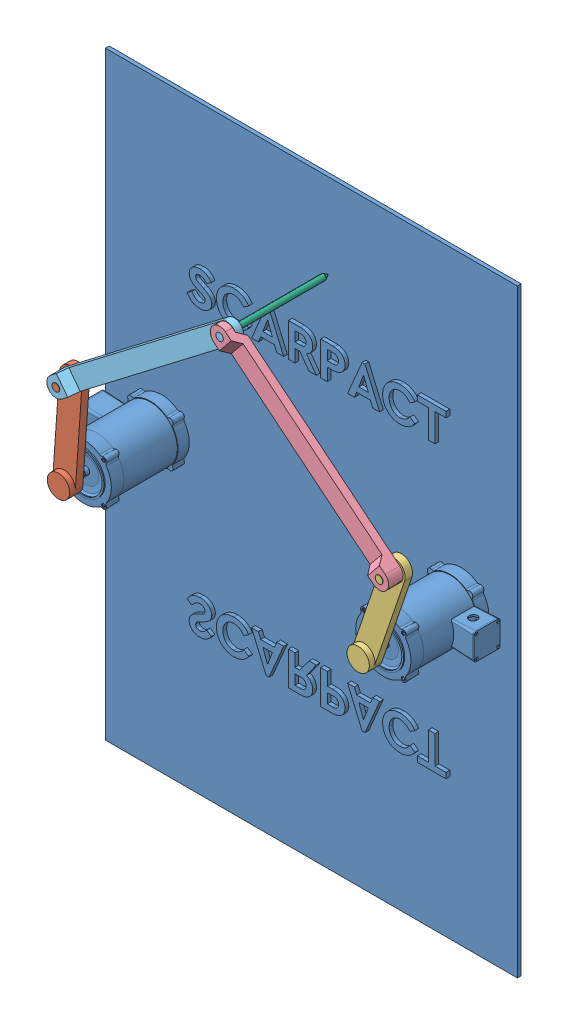
SolidWorks assembly SCARPACT, configuration Default. Lengths in mm.
Overall size (1100 1600 310.35).
6 component instances, 6 part files, 14 mates.
Components (placement in the parent):
- Base-1: Base [Default] at origin size (1100 1600 270.35)
- Link A1-1: Link A1 [Default] at (8.7744 124.6917 250.35) x (0.070195 0.997533 0) z (0 0 1) size (310 60 60)
- Link A2-1: Link A2 [Default] at (840.3034 118.3243 250.35) x (0.322428 0.946594 0) z (0 0 1) size (310 60 60)
- Link B1-1: Link B1 [Default] at (667.3575 410.2852 270.35) x (-0.775453 0.631406 0) z (0 0 1) size (600 50 39)
- Link B2-1: Link B2 [Default] at (250.4261 427.8389 269.85) x (0.793744 0.608252 0) z (0 0 1) size (600 50 39)
- Endeffector-1: Endeffector [Default] at (293.9198 383.4526 260.35) x (-0.62425 -0.781224 0) z (0 0 -1) size (15 15 250.35)
Mates (geometry in assembly coordinates):
- Coincident1: coincident aligned: plane of Base_Modified-1 through (0 0 0) normal (0 0 1)
- Coincident2: coincident aligned: plane of Base_Modified-1 through (0 0 0) normal (0 1 0)
- Concentric1: concentric anti-aligned: cylinder of Base_Modified-1 through (0 0 260.35) axis (0 0 1) radius 7.9375; cylinder of Link A1-1 through (0 0 260.35) axis (0 0 -1) radius 9.8426
- Coincident4: coincident anti-aligned: plane of Base_Modified-1 through (0 0 260.35) normal (0 0 1); plane of Link A1-1 through (0 0 260.35) normal (0 0 -1)
- Concentric3: concentric aligned: cylinder of Link A1-1 through (17.5487 249.3833 300.35) axis (0 0 -1) radius 10; cylinder of Link B2-1 through (17.5487 249.3833 299.35) axis (0 0 -1) radius 10
- Coincident6: coincident anti-aligned: plane of Link A1-1 through (0 0 260.35) normal (0 0 1); plane of Link B2-1 through (17.5487 249.3833 260.35) normal (0 0 -1)
- Concentric4: concentric anti-aligned: cylinder of Base_Modified-1 through (800 0 260.35) axis (0 0 1) radius 7.9375; cylinder of Link A2-1 through (800 0 260.35) axis (0 0 -1) radius 9.8426
- Coincident7: coincident anti-aligned: plane of Base_Modified-1 through (800 0 260.35) normal (0 0 1); plane of Link A2-1 through (800 0 260.35) normal (0 0 -1)
- Concentric5: concentric aligned: cylinder of Link A2-1 through (880.6069 236.6485 300.35) axis (0 0 -1) radius 10; cylinder of Link B1-1 through (880.6069 236.6485 299.35) axis (0 0 -1) radius 10
- Coincident8: coincident anti-aligned: plane of Link A2-1 through (800 0 260.35) normal (0 0 1); plane of Link B1-1 through (880.6069 236.6485 260.35) normal (0 0 -1)
- Concentric6: concentric aligned: cylinder of Link B1-1 through (454.108 583.9218 299.35) axis (0 0 -1) radius 10; cylinder of Link B2-1 through (454.108 583.9218 299.35) axis (0 0 -1) radius 10
- Coincident9: coincident: line of Base_Modified-1 through (0 0 212.598) axis (0 0 1)
- Concentric7: concentric anti-aligned: cylinder of Link B2-1 through (454.108 583.9218 299.35) axis (0 0 -1) radius 25; cylinder of Endeffector-1 through (454.108 583.9218 -21.2132) axis (0 0 1) radius 7.5
- Coincident13: coincident anti-aligned: plane of Link B2-1 through (17.5487 249.3833 260.35) normal (0 0 -1); plane of Endeffector-1 through (454.108 583.9218 260.35) normal (0 0 1)
